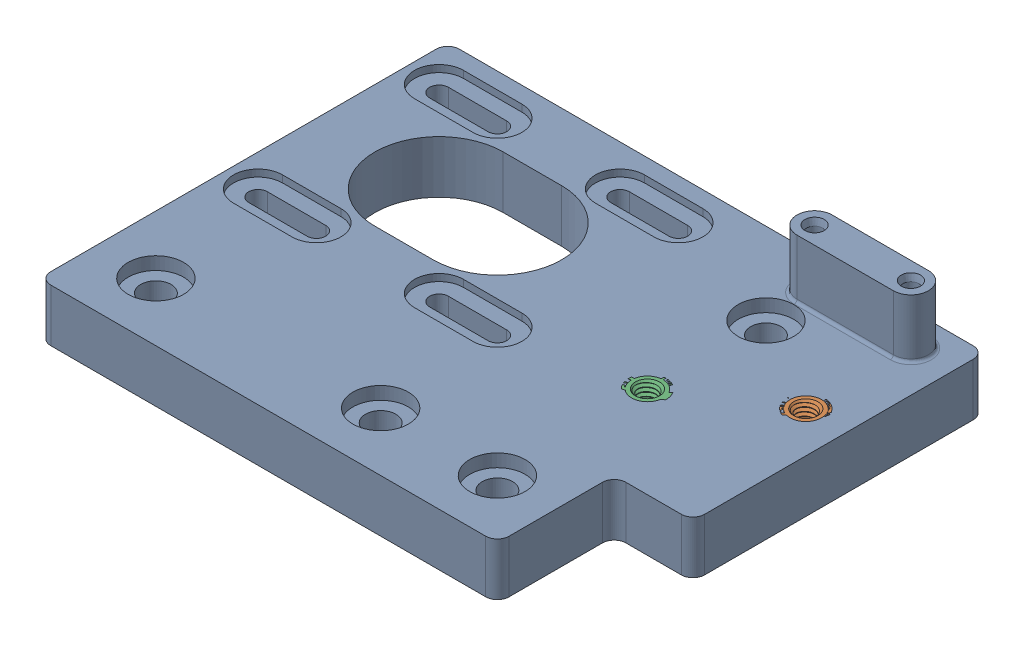
SolidWorks assembly right_motor_plate_with_inserts, configuration Default. Lengths in mm.
Overall size (92 19 70).
3 component instances, 2 part files, 0 mates.
Components (placement in the parent):
- motor_corner_bracket_Right Motor Corner Bracket-1: motor_corner_bracket_Right Motor Corner Bracket [Default] at (197.071 392.0105 15.3157) size (92 19 70)
- m4_heat_set_insert_long_94180A353_94180A353-1: m4_heat_set_insert_long_94180A353_94180A353 [Default] at (360.571 401.0105 -31.0093) size (6.35 8 6.35)
- m4_heat_set_insert_long_94180A353_94180A353-2: m4_heat_set_insert_long_94180A353_94180A353 [Default] at (344.071 401.0105 -20.3843) size (6.35 8 6.35)
